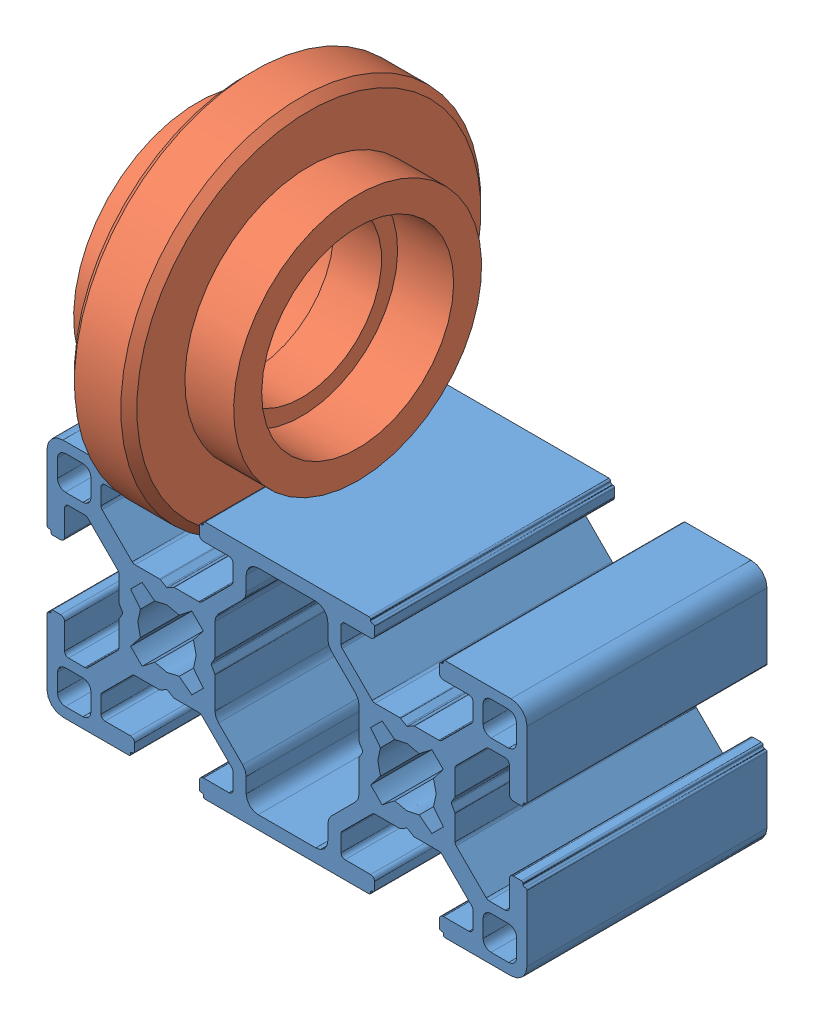
SolidWorks assembly Ролик СБ, configuration По умолчанию. Lengths in mm.
Overall size (60 71.64 52.29).
2 component instances, 2 part files, 2 mates.
Components (placement in the parent):
- 30х60х100-1: 30х60х100 [По умолчанию] at origin size (60 30 30)
- Ролик 8паз-1: Ролик 8паз [По умолчанию] at (-0.15 30.5 16.0189) x (1 0 0) z (0 0.177891 0.98405) size (20 45 45)
Mates (geometry in assembly coordinates):
- Совпадение1: coincident anti-aligned: plane of 30х60х100-1 through (-4.05 0 30) normal (1 0 0); plane of Ролик 8паз-1 through (-4.05 45.7528 13.2616) normal (-1 0 0)
- Касательность1: tangent anti-aligned: plane of 30х60х100-1 through (0 15 30) normal (0 1 0); cylinder of Ролик 8паз-1 through (-24.7688 30.5 16.0189) axis (-1 0 0) radius 15.5
